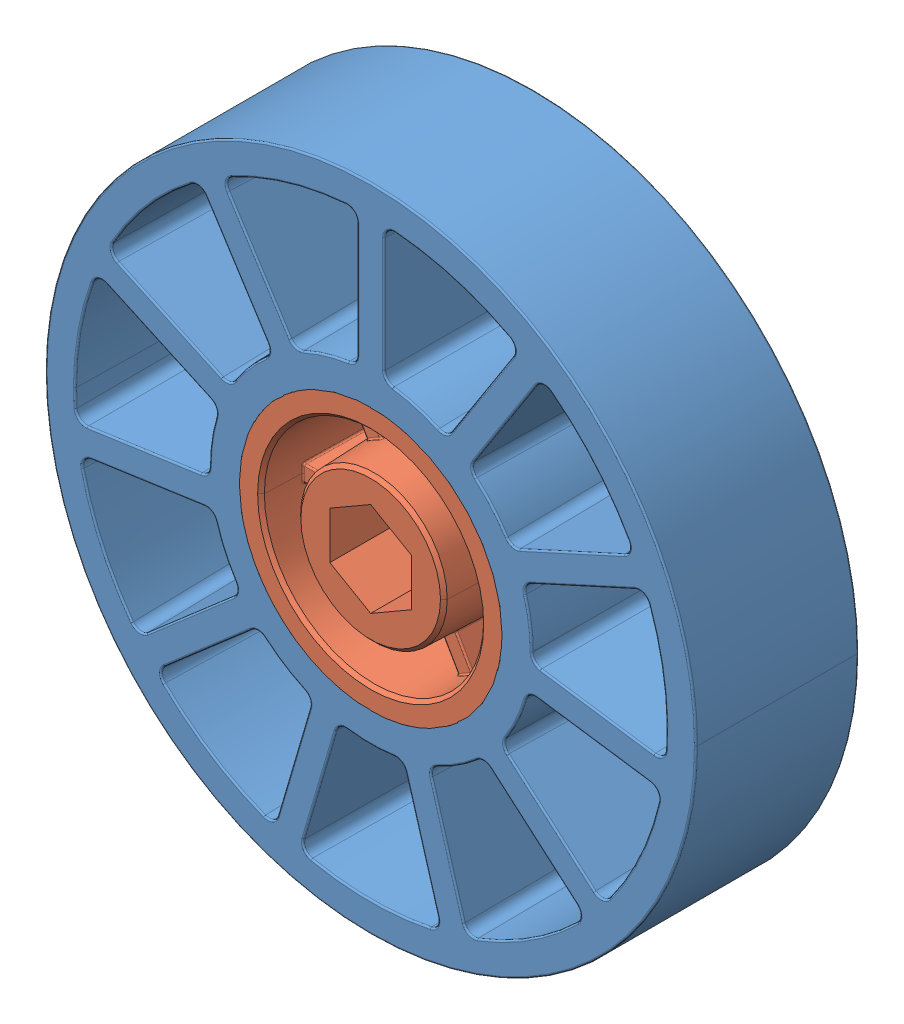
SolidWorks assembly am-3480 4IN 500Hex Compliant Wheel REV2.STEP, configuration Default. Lengths in mm.
Overall size (101.6 101.6 25.4).
2 component instances, 2 part files, 0 mates.
Components (placement in the parent):
- 4IN Compliant Wheel FINAL Overmold.STEP-1: 4IN Compliant Wheel FINAL Overmold.STEP [Default] at (-16.2374 3.8509 18.652) size (101.6 101.6 25.4)
- 2in Wheel Intergrated 0500 HEX Hub.STEP-1: 2in Wheel Intergrated 0500 HEX Hub.STEP [Default] at (-16.2374 3.8509 5.952) x (-1 0 0) z (0 0 -1) size (41.91 41.91 25.4)
